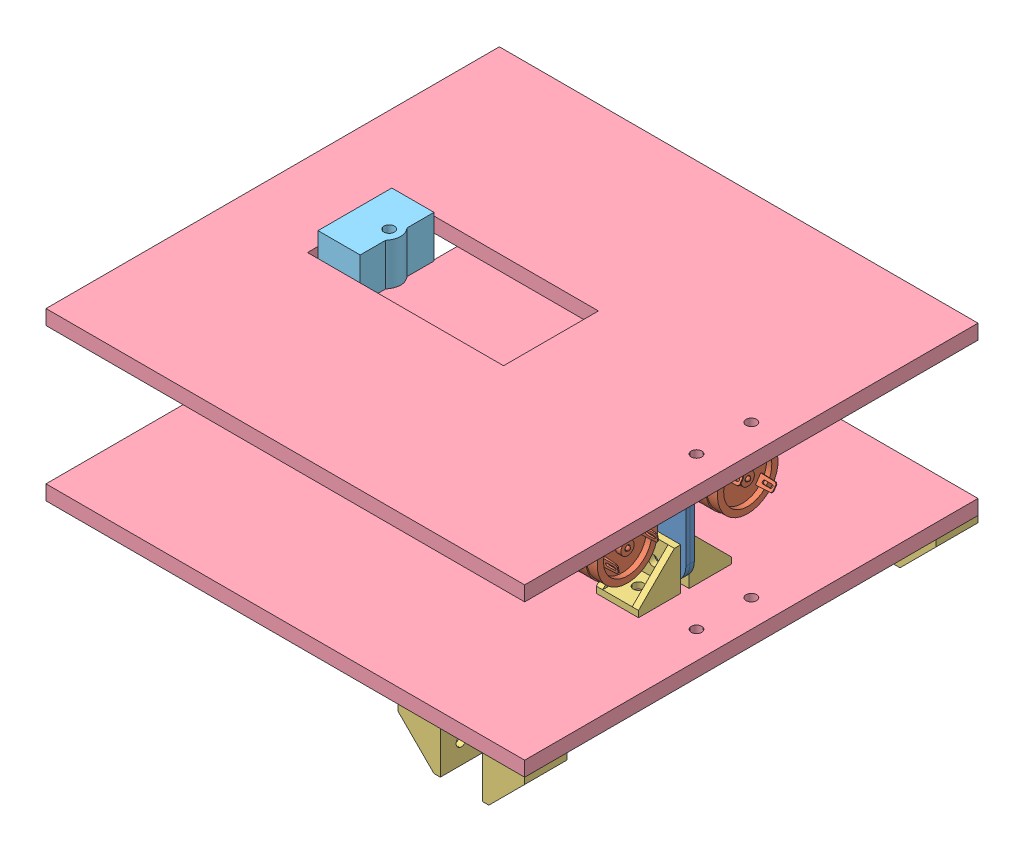
SolidWorks assembly CLAW ASSEM, configuration Default. Lengths in mm.
Overall size (227 105.5 215).
16 component instances, 5 part files, 47 mates.
Components (placement in the parent):
- MOTOR CLAMP-1: MOTOR CLAMP [Default] at (18.8124 38.0248 53.9381) size (68 60 57)
- MOTOR CLAMP-2: MOTOR CLAMP [Default] at (18.8124 38.0248 53.9381) x (1 0 0) z (0 0 -1) size (68 60 57)
- IG-32GM_Geared_DC_Motor-1: IG-32GM_Geared_DC_Motor [Default] at (46.6124 38.0248 25.4381) x (0 -0.561541 -0.827449) z (0 0.827449 -0.561541) size (32.25 89.06 32.25)
- IG-32GM_Geared_DC_Motor-2: IG-32GM_Geared_DC_Motor [Default] at (46.6124 38.0248 82.4381) x (0 -0.188025 0.982164) z (0 -0.982164 -0.188025) size (32.25 89.06 32.25)
- 2020CornerBracket.step-1: 2020CornerBracket.step [Default] at (50.3124 5.5248 55.9381) size (20 20 20)
- 2020CornerBracket.step-2: 2020CornerBracket.step [Default] at (30.3124 5.5248 51.9381) x (-1 0 0) z (0 0 -1) size (20 20 20)
- 2020CornerBracket.step-3: 2020CornerBracket.step [Default] at (30.3124 70.5248 55.9381) x (-1 0 0) z (0 0 1) size (20 20 20)
- 2020CornerBracket.step-4: 2020CornerBracket.step [Default] at (50.3124 70.5248 51.9381) x (1 0 0) z (0 0 -1) size (20 20 20)
- CLAW BASE-1: CLAW BASE [Default] at (-28.5983 -1.4752 53.9381) x (0 0 -1) z (0 1 0) size (215 227 7)
- S PART 3-1: S PART 3 [Default] at (-89.933 -7.9752 53.011) x (0 0 1) z (-1 0 0) size (35 20 22.01)
- CLAW BASE-2: CLAW BASE [Default] at (-28.5983 77.5248 53.9381) x (0 0 1) z (0 -1 0) size (215 227 7)
- S PART 3-2: S PART 3 [Default] at (-89.933 64.0248 53.011) x (0 0 1) z (-1 0 0) size (35 20 22.01)
- 2020CornerBracket.step-5: 2020CornerBracket.step [Default] at (41.8124 -1.4752 141.4381) x (0 0 -1) z (-1 0 0) size (20 20 20)
- 2020CornerBracket.step-6: 2020CornerBracket.step [Default] at (41.8124 -1.4752 -53.5619) x (0 0 -1) z (-1 0 0) size (20 20 20)
- 2020CornerBracket.step-7: 2020CornerBracket.step [Default] at (61.8124 -1.4752 161.4381) x (0 0 1) z (1 0 0) size (20 20 20)
- 2020CornerBracket.step-8: 2020CornerBracket.step [Default] at (61.8124 -1.4752 -53.5619) x (0 0 -1) z (0 -1 0) size (20 20 20)
Mates (geometry in assembly coordinates):
- Coincident1: coincident anti-aligned: plane of MOTOR CLAMP-1 through (42.8124 58.0248 53.9381) normal (0 0 -1); plane of MOTOR CLAMP-2 through (42.8124 18.0248 53.9381) normal (0 0 1)
- Coincident2: coincident aligned: plane of MOTOR CLAMP-1 through (-15.1876 8.0248 55.9381) normal (-1 0 0); plane of MOTOR CLAMP-2 through (-15.1876 68.0248 51.9381) normal (-1 0 0)
- Concentric1: concentric anti-aligned: cylinder of MOTOR CLAMP-1 through (40.3124 60.5248 0.9381) axis (0 0 1) radius 2.5853; cylinder of MOTOR CLAMP-2 through (40.3124 60.5248 106.9381) axis (0 0 -1) radius 2.5853
- Coincident3: coincident anti-aligned: plane of MOTOR CLAMP-2 through (-13.1876 8.0248 -3.0619) normal (1 0 0); plane of IG-32GM_Geared_DC_Motor-1 through (-13.1876 38.0248 25.4381) normal (-1 0 0)
- Concentric2: concentric anti-aligned: cylinder of MOTOR CLAMP-2 through (39.8124 38.0248 25.4381) axis (-1 0 0) radius 10; cylinder of IG-32GM_Geared_DC_Motor-1 through (-16.1876 38.0248 25.4381) axis (1 0 0) radius 10
- Tangent1: tangent anti-aligned: cylinder of MOTOR CLAMP-2 through (39.8124 49.8028 25.4381) axis (-1 0 0) radius 1; cylinder of IG-32GM_Geared_DC_Motor-1 through (-7.6876 50.5258 27.8312) axis (-1 0 0) radius 1.5
- Coincident4: coincident anti-aligned: plane of MOTOR CLAMP-1 through (-13.1876 68.0248 110.9381) normal (1 0 0); plane of IG-32GM_Geared_DC_Motor-2 through (-13.1876 38.0248 82.4381) normal (-1 0 0)
- Concentric4: concentric anti-aligned: cylinder of MOTOR CLAMP-1 through (39.8124 38.0248 82.4381) axis (-1 0 0) radius 10; cylinder of IG-32GM_Geared_DC_Motor-2 through (-16.1876 38.0248 82.4381) axis (1 0 0) radius 10
- Tangent3: tangent anti-aligned: cylinder of MOTOR CLAMP-1 through (39.8124 29.6966 90.7663) axis (-1 0 0) radius 1; cylinder of IG-32GM_Geared_DC_Motor-2 through (-7.6876 27.4931 89.5853) axis (-1 0 0) radius 1.5
- Concentric7: concentric anti-aligned: cylinder of MOTOR CLAMP-1 through (40.3124 15.5248 0.9381) axis (0 0 1) radius 2.5853; cylinder of 2020CornerBracket.step-1 through (40.3124 15.5248 75.9381) axis (0 0 -1) radius 2.5
- Coincident5: coincident anti-aligned: plane of MOTOR CLAMP-1 through (42.8124 58.0248 55.9381) normal (0 0 1); plane of 2020CornerBracket.step-1 through (50.3124 5.5248 55.9381) normal (0 0 -1)
- Parallel4: parallel aligned: plane of MOTOR CLAMP-1 through (-15.1876 8.0248 55.9381) normal (0 -1 0); plane of 2020CornerBracket.step-1 through (40.3124 5.5248 65.9381) normal (0 -1 0)
- Coincident7: coincident anti-aligned: plane of MOTOR CLAMP-2 through (42.8124 18.0248 51.9381) normal (0 0 -1); plane of 2020CornerBracket.step-2 through (30.3124 5.5248 51.9381) normal (0 0 1)
- Concentric8: concentric anti-aligned: cylinder of MOTOR CLAMP-2 through (40.3124 15.5248 106.9381) axis (0 0 -1) radius 2.5853; cylinder of 2020CornerBracket.step-2 through (40.3124 15.5248 31.9381) axis (0 0 1) radius 2.5
- Parallel5: parallel aligned: plane of MOTOR CLAMP-2 through (-15.1876 8.0248 51.9381) normal (0 -1 0); plane of 2020CornerBracket.step-2 through (40.3124 5.5248 41.9381) normal (0 -1 0)
- Coincident9: coincident anti-aligned: plane of MOTOR CLAMP-1 through (42.8124 58.0248 55.9381) normal (0 0 1); plane of 2020CornerBracket.step-3 through (30.3124 70.5248 55.9381) normal (0 0 -1)
- Coincident11: coincident anti-aligned: plane of MOTOR CLAMP-2 through (42.8124 18.0248 51.9381) normal (0 0 -1); plane of 2020CornerBracket.step-4 through (50.3124 70.5248 51.9381) normal (0 0 1)
- Concentric9: concentric anti-aligned: cylinder of MOTOR CLAMP-1 through (40.3124 60.5248 0.9381) axis (0 0 1) radius 2.5853; cylinder of 2020CornerBracket.step-3 through (40.3124 60.5248 75.9381) axis (0 0 -1) radius 2.5
- Concentric10: concentric anti-aligned: cylinder of MOTOR CLAMP-2 through (40.3124 60.5248 106.9381) axis (0 0 -1) radius 2.5853; cylinder of 2020CornerBracket.step-4 through (40.3124 60.5248 31.9381) axis (0 0 1) radius 2.5
- Parallel6: parallel aligned: plane of MOTOR CLAMP-2 through (-15.1876 68.0248 51.9381) normal (0 1 0); plane of 2020CornerBracket.step-4 through (40.3124 70.5248 41.9381) normal (0 1 0)
- Parallel7: parallel aligned: plane of MOTOR CLAMP-1 through (-15.1876 68.0248 55.9381) normal (0 1 0); plane of 2020CornerBracket.step-3 through (40.3124 70.5248 65.9381) normal (0 1 0)
- Coincident12: coincident anti-aligned: plane of 2020CornerBracket.step-1 through (40.3124 5.5248 65.9381) normal (0 -1 0); plane of CLAW BASE-1 through (-28.5983 5.5248 53.9381) normal (0 1 0)
- Width1: width anti-aligned: plane of CLAW BASE-1 through (-28.5983 5.5248 161.4381) normal (0 0 1); plane of CLAW BASE-1 through (-28.5983 5.5248 -53.5619) normal (0 0 -1); plane of 2020CornerBracket.step-2 through (50.3124 5.5248 31.9381) normal (0 0 -1); plane of 2020CornerBracket.step-1 through (30.3124 5.5248 75.9381) normal (0 0 1)
- Width2: width anti-aligned: plane of CLAW BASE-1 through (-28.5983 5.5248 161.4381) normal (0 0 1); plane of CLAW BASE-1 through (-28.5983 5.5248 -53.5619) normal (0 0 -1); plane of MOTOR CLAMP-2 through (42.8124 18.0248 51.9381) normal (0 0 -1); plane of MOTOR CLAMP-1 through (42.8124 58.0248 55.9381) normal (0 0 1)
- Distance2: distance = 95 mm aligned: plane of MOTOR CLAMP-2 through (-13.1876 8.0248 -3.0619) normal (1 0 0); plane of CLAW BASE-1 through (81.8124 5.5248 53.9381) normal (1 0 0)
- Coincident15: coincident anti-aligned: plane of CLAW BASE-1 through (-106.1876 5.5248 53.9381) normal (1 0 0); plane of S PART 3-1 through (-106.1876 12.0248 36.4381) normal (-1 0 0)
- Coincident16: coincident anti-aligned: plane of CLAW BASE-1 through (-106.1876 5.5248 53.9381) normal (1 0 0); plane of S PART 3-1 through (-106.1876 12.0248 36.4381) normal (-1 0 0)
- Width3: width aligned: plane of CLAW BASE-1 through (-28.5983 5.5248 76.4381) normal (0 0 -1); plane of CLAW BASE-1 through (-28.5983 5.5248 31.4381) normal (0 0 1); plane of S PART 3-1 through (-86.1876 12.0248 36.4381) normal (0 0 -1); plane of S PART 3-1 through (-106.1876 12.0248 71.4381) normal (0 0 1)
- Coincident17: coincident anti-aligned: plane of 2020CornerBracket.step-4 through (40.3124 70.5248 41.9381) normal (0 1 0); plane of CLAW BASE-2 through (-28.5983 70.5248 53.9381) normal (0 -1 0)
- Coincident19: coincident aligned: plane of CLAW BASE-1 through (-28.5983 5.5248 -53.5619) normal (0 0 -1); plane of CLAW BASE-2 through (-28.5983 70.5248 -53.5619) normal (0 0 -1)
- Concentric11: concentric anti-aligned: cylinder of CLAW BASE-1 through (68.8124 5.5248 40.9381) axis (0 -1 0) radius 2.5; cylinder of CLAW BASE-2 through (68.8124 70.5248 40.9381) axis (0 1 0) radius 2.5
- Coincident20: coincident anti-aligned: plane of CLAW BASE-2 through (-106.1876 70.5248 53.9381) normal (1 0 0); plane of S PART 3-2 through (-106.1876 84.0248 36.4381) normal (-1 0 0)
- Concentric12: concentric aligned: cylinder of S PART 3-1 through (-89.933 12.0248 53.9381) axis (0 -1 0) radius 2.5; cylinder of S PART 3-2 through (-89.933 84.0248 53.9381) axis (0 -1 0) radius 2.5
- Coincident21: coincident anti-aligned: plane of CLAW BASE-2 through (-106.1876 70.5248 53.9381) normal (1 0 0); plane of S PART 3-2 through (-106.1876 84.0248 36.4381) normal (-1 0 0)
- Width4: width aligned: plane of CLAW BASE-2 through (-28.5983 70.5248 31.4381) normal (0 0 1); plane of S PART 3-2 through (-28.5983 70.5248 76.4381) normal (0 0 -1); plane of CLAW BASE-2 through (-106.1876 84.0248 71.4381) normal (0 0 1); plane of S PART 3-2 through (-86.1876 84.0248 36.4381) normal (0 0 -1)
- Width5: width anti-aligned: plane of S PART 3-2 through (-84.1772 84.0248 54.2593) normal (0 1 0); plane of CLAW BASE-2 through (-84.1772 64.0248 54.2593) normal (0 -1 0); plane of S PART 3-2 through (-28.5983 70.5248 53.9381) normal (0 -1 0); plane of CLAW BASE-2 through (-28.5983 77.5248 53.9381) normal (0 1 0)
- Width6: width anti-aligned: plane of S PART 3-1 through (-84.1772 -7.9752 54.2593) normal (0 -1 0); plane of CLAW BASE-1 through (-84.1772 12.0248 54.2593) normal (0 1 0); plane of S PART 3-1 through (-28.5983 5.5248 53.9381) normal (0 1 0); plane of CLAW BASE-1 through (-28.5983 -1.4752 53.9381) normal (0 -1 0)
- Coincident44: coincident anti-aligned: plane of CLAW BASE-1 through (-28.5983 -1.4752 53.9381) normal (0 -1 0); plane of 2020CornerBracket.step-5 through (31.8124 -1.4752 151.4381) normal (0 1 0)
- Coincident45: coincident anti-aligned: plane of CLAW BASE-1 through (-28.5983 -1.4752 53.9381) normal (0 -1 0); plane of 2020CornerBracket.step-8 through (61.8124 -1.4752 -53.5619) normal (0 1 0)
- Coincident46: coincident anti-aligned: plane of CLAW BASE-1 through (-28.5983 -1.4752 53.9381) normal (0 -1 0); plane of 2020CornerBracket.step-7 through (71.8124 -1.4752 151.4381) normal (0 1 0)
- Coincident47: coincident aligned: plane of CLAW BASE-1 through (-28.5983 5.5248 161.4381) normal (0 0 1); plane of 2020CornerBracket.step-7 through (81.8124 -1.4752 161.4381) normal (0 0 1)
- Coincident48: coincident aligned: plane of CLAW BASE-1 through (-28.5983 5.5248 -53.5619) normal (0 0 -1); plane of 2020CornerBracket.step-8 through (61.8124 -21.4752 -53.5619) normal (0 0 -1)
- Coincident50: coincident anti-aligned: plane of CLAW BASE-1 through (-28.5983 -1.4752 53.9381) normal (0 -1 0); plane of 2020CornerBracket.step-6 through (31.8124 -1.4752 -43.5619) normal (0 1 0)
- Coincident55: coincident aligned: plane of CLAW BASE-1 through (81.8124 5.5248 53.9381) normal (1 0 0); plane of 2020CornerBracket.step-8 through (81.8124 -11.4752 -43.5619) normal (1 0 0)
- Coincident56: coincident aligned: plane of CLAW BASE-1 through (81.8124 5.5248 53.9381) normal (1 0 0); plane of 2020CornerBracket.step-7 through (81.8124 -1.4752 141.4381) normal (1 0 0)
- Coincident61: coincident aligned: plane of CLAW BASE-1 through (-28.5983 5.5248 -53.5619) normal (0 0 -1); plane of 2020CornerBracket.step-6 through (21.8124 -1.4752 -53.5619) normal (0 0 -1)
- Coincident63: coincident aligned: plane of CLAW BASE-1 through (-28.5983 5.5248 161.4381) normal (0 0 1); plane of 2020CornerBracket.step-5 through (41.8124 -1.4752 161.4381) normal (0 0 1)
